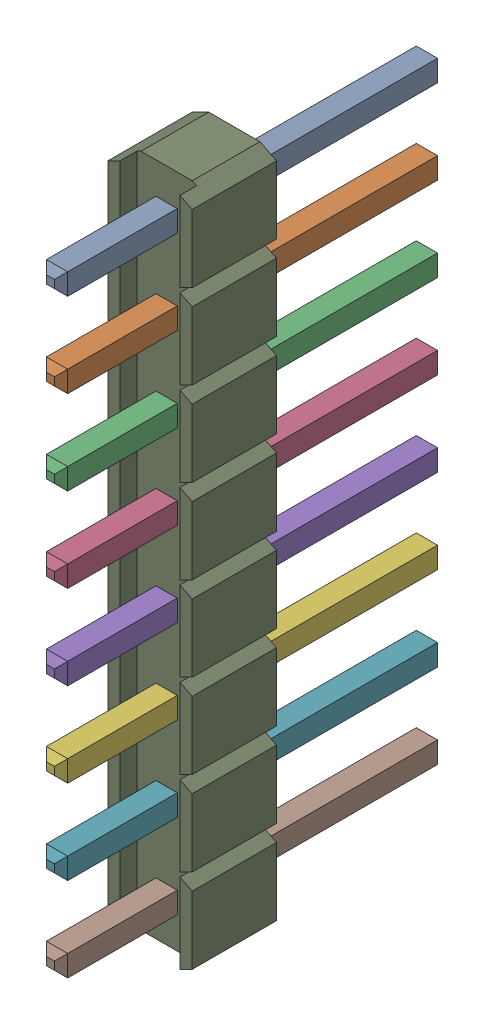
SolidWorks assembly Open CASCADE STEP translator 6.8 1.3, configuration ﾃﾞﾌｫﾙﾄ. Lengths in mm.
Overall size (2.54 20.32 11.54).
9 component instances, 9 part files, 0 mates.
Components (placement in the parent):
- Header8_2.54mm-1: Header8_2.54mm [ﾃﾞﾌｫﾙﾄ] at (1.3969 10.3123 -1.2168) x (0 -1 0) z (1 0 0) size (0.64 11.54 0.64)
- Header8_2.54mm-2-1: Header8_2.54mm-2 [ﾃﾞﾌｫﾙﾄ] at (1.3969 10.3123 -1.2168) x (0 -1 0) z (1 0 0) size (0.64 11.54 0.64)
- Header8_2.54mm-3-1: Header8_2.54mm-3 [ﾃﾞﾌｫﾙﾄ] at (1.3969 10.3123 -1.2168) x (0 -1 0) z (1 0 0) size (0.64 11.54 0.64)
- Header8_2.54mm-4-1: Header8_2.54mm-4 [ﾃﾞﾌｫﾙﾄ] at (1.3969 10.3123 -1.2168) x (0 -1 0) z (1 0 0) size (0.64 11.54 0.64)
- Header8_2.54mm-5-1: Header8_2.54mm-5 [ﾃﾞﾌｫﾙﾄ] at (1.3969 10.3123 -1.2168) x (0 -1 0) z (1 0 0) size (0.64 11.54 0.64)
- Header8_2.54mm-6-1: Header8_2.54mm-6 [ﾃﾞﾌｫﾙﾄ] at (1.3969 10.3123 -1.2168) x (0 -1 0) z (1 0 0) size (0.64 11.54 0.64)
- Header8_2.54mm-7-1: Header8_2.54mm-7 [ﾃﾞﾌｫﾙﾄ] at (1.3969 10.3123 -1.2168) x (0 -1 0) z (1 0 0) size (0.64 11.54 0.64)
- Header8_2.54mm-8-1: Header8_2.54mm-8 [ﾃﾞﾌｫﾙﾄ] at (1.3969 10.3123 -1.2168) x (0 -1 0) z (1 0 0) size (0.64 11.54 0.64)
- Header8_2.54mm-9-1: Header8_2.54mm-9 [ﾃﾞﾌｫﾙﾄ] at (1.3969 10.3123 -1.2168) x (0 -1 0) z (1 0 0) size (20.32 2.54 2.54)
